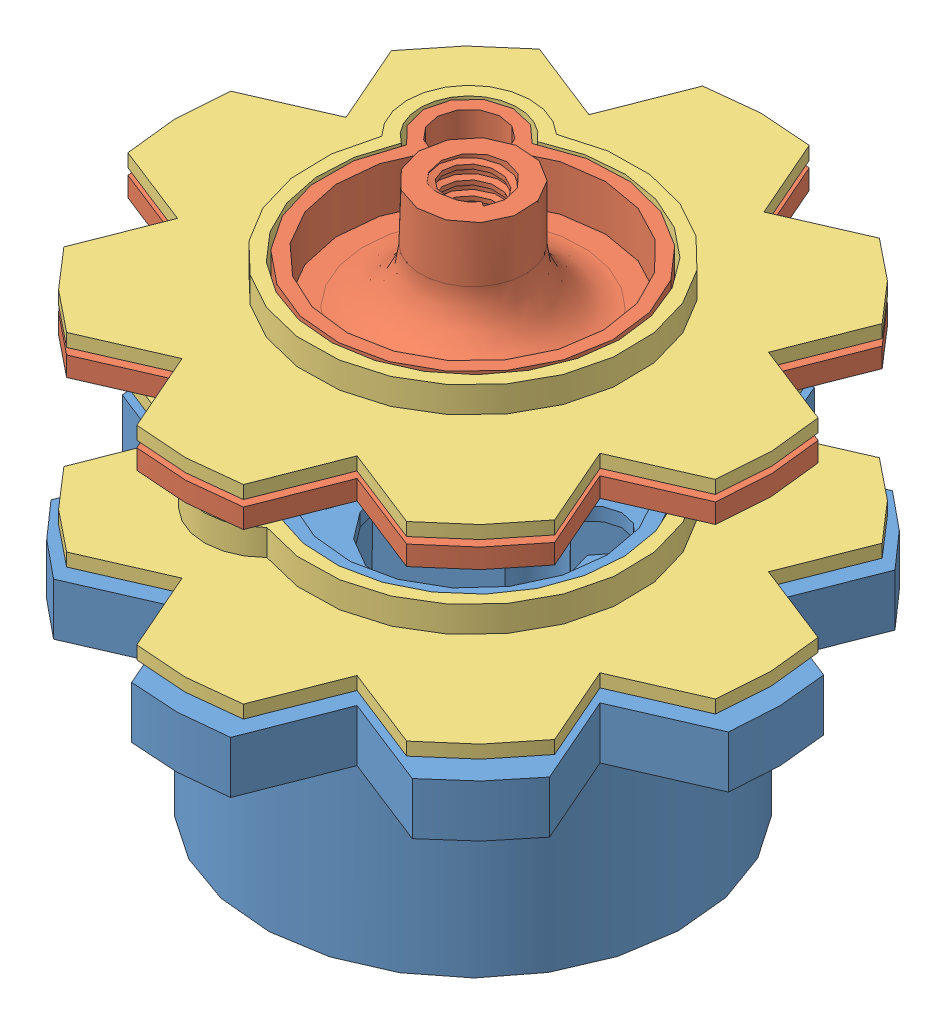
SolidWorks assembly 5mm Stepper Syringe Pump Assembly, configuration Default. Lengths in mm.
Overall size (124.1 83.57 124.1).
4 component instances, 3 part files, 10 mates.
Components (placement in the parent):
- 5mm stepper Base-1: 5mm stepper Base [Default] x (0.916529 0 -0.399969) z (0.399969 0 0.916529) size (90.21 51.87 90.21)
- 3-8ths acme pusher-1: 3-8ths acme pusher [Default] at (0 63.2281 0) x (-0.848171 0 -0.529722) z (0.529722 0 -0.848171) size (90.06 20.35 90.06)
- ClampRing-1: ClampRing [Default] at (0 67.2281 0) x (0.941414 0 -0.337253) z (0 1 0) size (89.15 89.15 6)
- ClampRing-2: ClampRing [Default] at (0 38 0) x (-0.337253 0 -0.941414) z (0 1 0) size (89.15 89.15 6)
Mates (geometry in assembly coordinates):
- Concentric1: concentric aligned: cylinder of 5mm stepper Base-1 through (0 0 0) axis (0 -1 0) radius 13; cylinder of 3-8ths acme pusher-1 through (0 63.2281 0) axis (0 -1 0) radius 5.05
- Concentric2: concentric: cylinder of 5mm stepper Base-1 through (0 0 0) axis (0 -1 0) radius 13; point of assembly
- Coincident2: coincident anti-aligned: plane of 5mm stepper Base-1 through (29.7872 0 -12.999) normal (0 -1 0); plane of assembly through (0 0 0) normal (0 1 0)
- Distance1: distance = 1 mm anti-aligned: plane of ClampRing-1 through (0 67.2281 0) normal (0 -1 0); plane of 3-8ths acme pusher-1 through (-38.2101 66.2281 -23.864) normal (0 1 0)
- Concentric3: concentric aligned: circle of 3-8ths acme pusher-1; cylinder of ClampRing-1 through (0 69.2281 0) axis (0 -1 0) radius 22.5
- Coincident6: coincident: plane of 3-8ths acme pusher-1 through (13.7989 63.2281 31.6202) normal (-0.365263 0 0.930904); plane of ClampRing-1 through (10.1992 69.2281 23.3715) normal (-0.365263 0 0.930904)
- Coincident11: coincident: plane of 5mm stepper Base-1 through (13.7989 28 31.6202) normal (-0.365263 0 0.930904); plane of ClampRing-2 through (-32.9244 40 6.4509) normal (-0.365263 0 0.930904)
- Parallel1: parallel: plane of 5mm stepper Base-1 through (31.6202 28 -13.7989) normal (0.365263 0 -0.930904); plane of ClampRing-2 through (-10.1992 40 -23.3715) normal (0.365263 0 -0.930904)
- Concentric8: concentric anti-aligned: circle of 5mm stepper Base-1; circle of ClampRing-2
- Distance3: distance = 2 mm anti-aligned: plane of ClampRing-2 through (0 38 0) normal (0 -1 0); plane of 5mm stepper Base-1 through (20.6219 36 -8.9993) normal (0 1 0)
